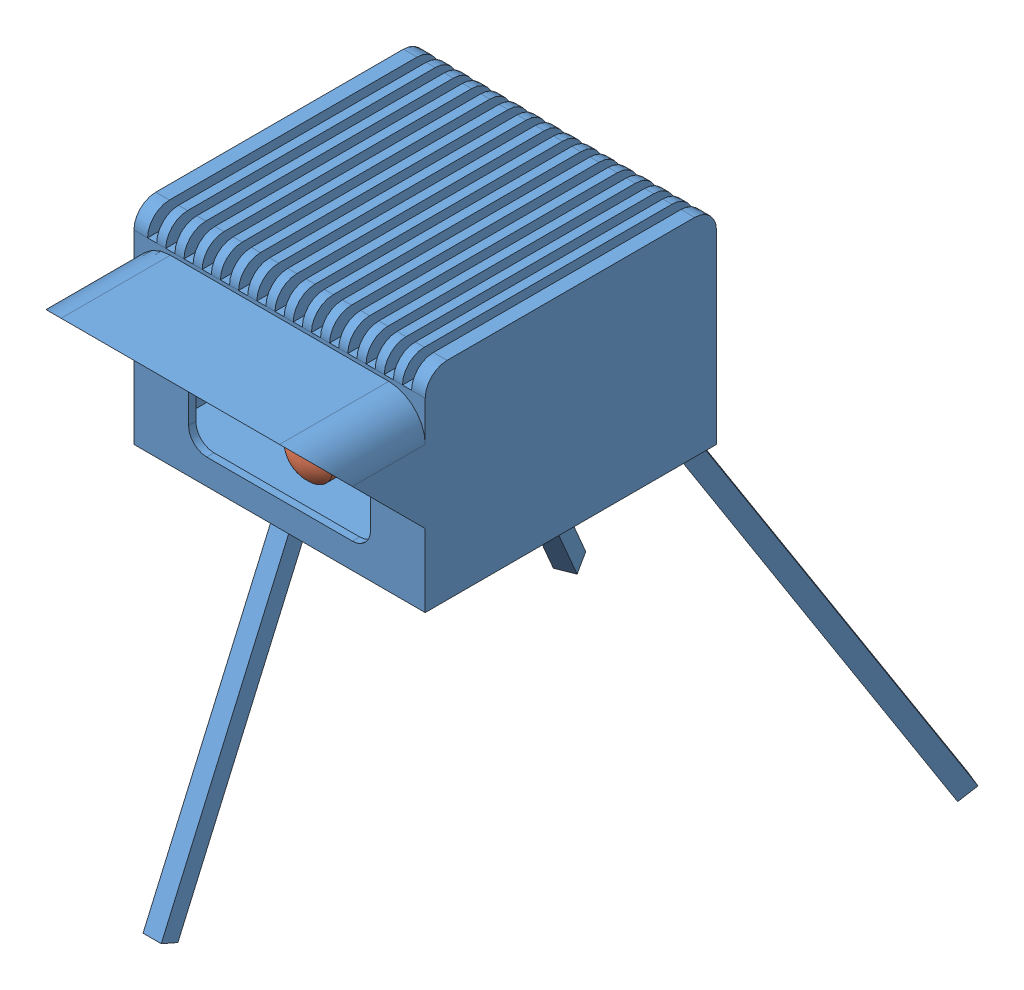
SolidWorks assembly vision_mast, configuration Default. Lengths in mm.
Overall size (132.05 202.66 218.74).
25 component instances, 12 part files, 4 mates.
Components (placement in the parent):
- case_bottom-2: case_bottom [Default] at (37.4546 42.9039 85.1077) size (132.05 202.66 218.74)
- PS3Eye-1: PS3Eye [Default] at (37.4546 73.3839 110.5077) size (76.2 50.8 18.87)
- TX2-3: TX2 [Default] at (75.6014 86.4269 53.8192) x (-1 0 0) z (0 1 0) size (87.07 50.04 12.4)
  - 244-83310-1000-C03_ASM-1: 244-83310-1000-C03_ASM [Default] at origin size (87 50 7.77)
    - 142-83310-1000-C03-1: 142-83310-1000-C03 [Default] at origin size (87 50 1.16)
    - 080-0550-000_2-1: 080-0550-000_2 [Default] at (-2.36 33.789 1.164) size (3.63 4.07 1.47)
    - 080-0550-000_2-2: 080-0550-000_2 [Default] at (-2.36 28.232 1.164) size (3.63 4.07 1.47)
    - 080-1337-000_1-1: 080-1337-000_1 [Default] at (39.5 3.4 0) x (1 0 0) z (0 0 -1) size (70.16 10.74 5.05)
  - P3310-BOTTOM-COVER--CNC-0316-1: P3310-BOTTOM-COVER--CNC-0316 [Default] at (83 8.88 -0.1484) x (-1 0 0) z (0 -1 0) size (87.03 9.23 36.85)
  - TTP-186-DIE-REFERENCE-C00_ASM-1: TTP-186-DIE-REFERENCE-C00_ASM [Default] at (0.432 5.918 1.244) size (87.07 50.03 8.27)
    - 094-0021-004_1-1: 094-0021-004_1 [Default] at origin size (87.07 50.03 6.1)
    - 153-0369-000-PRELOAD-1: 153-0369-000-PRELOAD [Default] at (26.3174 29.151 5) x (1 0 0) z (0 1 0) size (8.1 3.29 7.91)
    - 153-0369-000-PRELOAD-2: 153-0369-000-PRELOAD [Default] at (51.8674 29.151 5) x (1 0 0) z (0 1 0) size (8.1 3.29 7.91)
    - 153-0369-000-PRELOAD-3: 153-0369-000-PRELOAD [Default] at (39.0874 5.9953 5) x (1 0 0) z (0 1 0) size (8.1 3.29 7.91)
    - PIN_8_00-DIE-REFERENCE-P3310-1: PIN_8_00-DIE-REFERENCE-P3310 [Default] at (0 0 -1.2) x (-1 0 0) z (0 1 0) size (2 8 2)
    - PIN_8_00-DIE-REFERENCE-P3310-2: PIN_8_00-DIE-REFERENCE-P3310 [Default] at (78.138 30.162 -1.2) x (-1 0 0) z (0 1 0) size (2 8 2)
    - 153-0368-000-1: 153-0368-000 [Default] at (39.0874 5.9953 1.73) x (-1 0 0) z (0 1 0) size (4.25 3.76 4.25)
    - 153-0368-000-2: 153-0368-000 [Default] at (26.3174 29.151 1.73) x (-1 0 0) z (0 1 0) size (4.25 3.76 4.25)
    - 153-0368-000-3: 153-0368-000 [Default] at (51.8674 29.151 1.73) x (-1 0 0) z (0 1 0) size (4.25 3.76 4.25)
    - PRESSURE-PLATE-P3310-C01-1: PRESSURE-PLATE-P3310-C01 [Default] at (39.0874 18.8953 2.9656) x (-1 0 0) z (0 -1 0) size (30.37 2.6 29.12)
  - 155-0343-000-1: 155-0343-000 [Default] at (79 21 -1.1784) x (-1 0 0) z (0 0 -1) size (5.62 5.63 8.16)
  - 155-0343-000-2: 155-0343-000 [Default] at (0 21 -1.1784) x (-1 0 0) z (0 0 -1) size (5.62 5.63 8.16)
  - 153-0368-000-1: 153-0368-000 [Default] at (68.1416 45.009 3.6756) x (-1 0 0) z (0 0 1) size (4.25 3.76 4.25)
  - 153-0368-000-2: 153-0368-000 [Default] at (31 45.009 3.6756) x (-1 0 0) z (0 0 1) size (4.25 3.76 4.25)
  - 153-0368-000-3: 153-0368-000 [Default] at (11 45.009 3.6756) x (-1 0 0) z (0 0 1) size (4.25 3.76 4.25)
Mates (geometry in assembly coordinates):
- Coincident2: coincident anti-aligned: plane of case_bottom-2 through (-0.6454 96.2439 110.5077) normal (0 0 1); plane of PS3Eye-1 through (37.4546 73.3839 110.5077) normal (0 0 -1)
- Parallel1: parallel aligned: plane of case_bottom-2 through (37.4546 96.2439 85.1077) normal (0 1 0); plane of PS3Eye-1 through (-0.6454 98.7839 113.0477) normal (0 1 0)
- Coincident4: coincident anti-aligned: circle of case_bottom-2; cylinder of PS3Eye-1 through (12.0546 86.0839 129.3808) axis (0 0 -1) radius 1.5875
- Distance1: distance = 48.057 mm aligned: plane of TX2-3/TTP-186-DIE-REFERENCE-C00_ASM-1/094-0021-004_1-1 through (75.1694 93.5009 59.7372) normal (0 1 0); plane of case_bottom-2 through (37.4546 45.4439 85.1077) normal (0 1 0)
